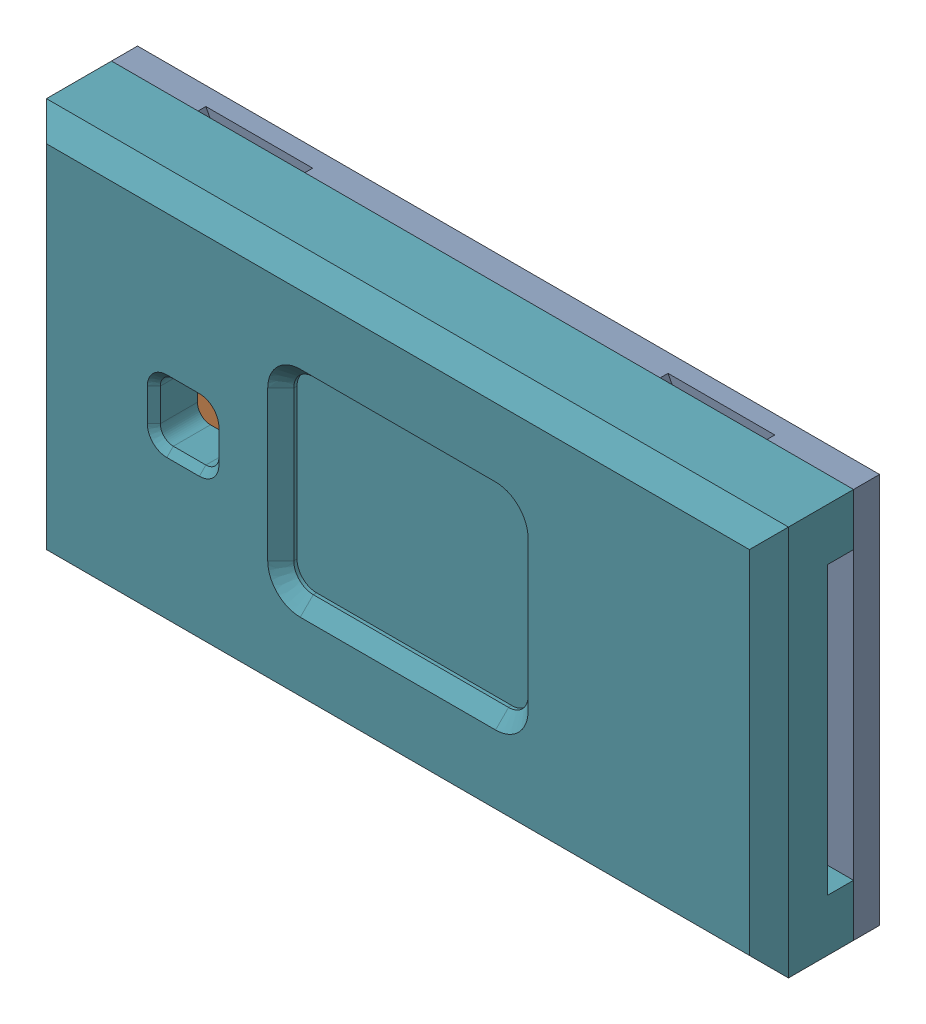
SolidWorks assembly _WERKST_X2_00FC_X0_CK-RAISONANCE-KOMPLETT_1, configuration Default. Lengths in mm.
Overall size (114 60 20).
8 component instances, 5 part files, 0 mates.
Components (placement in the parent):
- 071-900_Geh_X2_00E4_X0_use-Unterteil_1-1: 071-900_Geh_X2_00E4_X0_use-Unterteil_1 [Default] at origin size (114 60 11.7)
- _Platine_Dummy_komplett-neu_1-1: _PLATINE_DUMMY_KOMPLETT-NEU_1 [Default] at (7 30 11.7) size (107 55 13.93)
  - 071-905_RAISONANCE-Dummy-Platine_1-1: 071-905_RAISONANCE-Dummy-Platine_1 [Default] at origin size (107 55 1.6)
  - Sicherungshalter_1-1: Sicherungshalter_1 [Default] at (76.2 0 0) x (0 -1 0) z (1 0 0) size (24.76 13.63 6.5)
  - Sicherungshalter_1-2: Sicherungshalter_1 [Default] at (89.2 0 0) x (0 -1 0) z (1 0 0) size (24.76 13.63 6.5)
  - Schmelzsicherung 5x20_1-1: Schmelzsicherung 5x20_1 [Default] at (76.2 0 -6.5665) x (0.550409 0 -0.834895) z (0 1 0) size (5.1 5.1 20)
  - Schmelzsicherung 5x20_1-2: Schmelzsicherung 5x20_1 [Default] at (89.2 0 -6.5665) x (-0.333916 0 -0.942603) z (0 1 0) size (5.1 5.1 20)
- 071-901a_Geh_X2_00E4_X0_use-Oberteil_1-1: 071-901a_Geh_X2_00E4_X0_use-Oberteil_1 [Default] at (0 60 20) x (1 0 0) z (0 0 -1) size (114 60 13.01)
